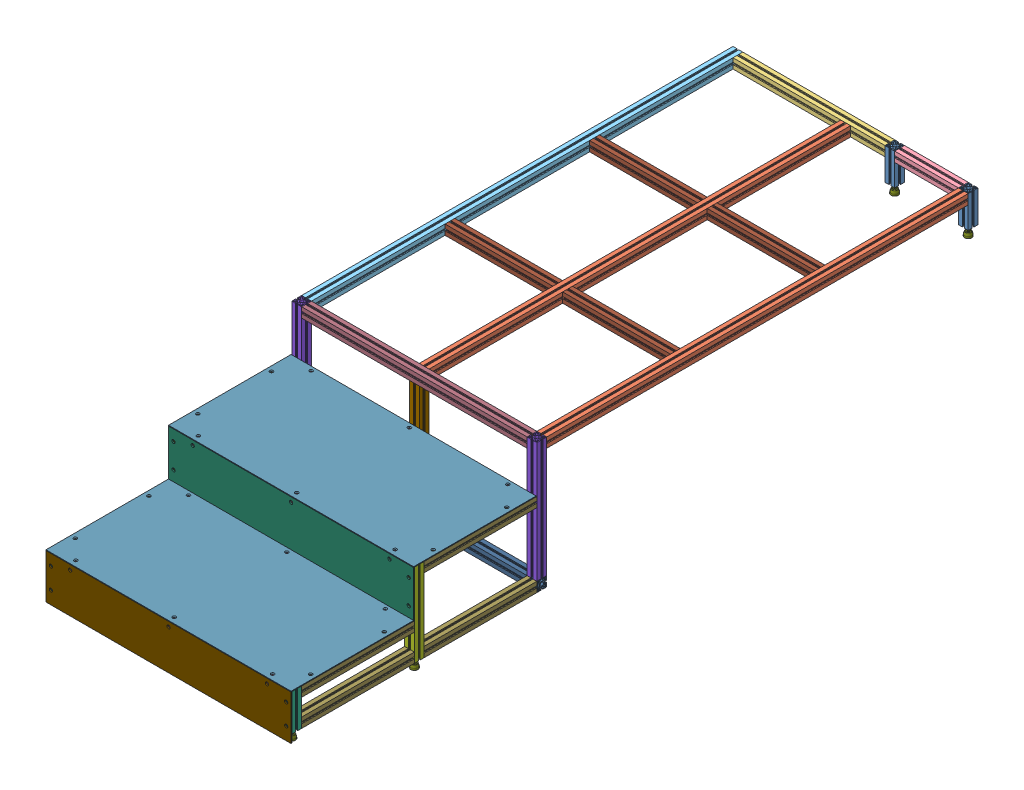
SolidWorks assembly LustroPd4 00-1-00, configuration Domyślna. Lengths in mm.
Overall size (1000 567 2803).
44 component instances, 18 part files, 0 mates.
Components (placement in the parent):
- LustroProfil 40x40x130-1: LustroProfil 40x40x130 [Default] at (20 -130 -1759.796) x (0 0 1) z (0 -1 0) size (40 40 130)
- LustroProfil 40x40x130-2: LustroProfil 40x40x130 [Default] at (-280 -130 -1759.796) x (0 0 1) z (0 -1 0) size (40 40 130)
- LustroProfil 40x40x1720-1: LustroProfil 40x40x1720 [Default] at (-20 -40 0) size (40 40 1720)
- LustroProfil 40x40x1720-2: LustroProfil 40x40x1720 [Default] at (-500 -40 0) size (40 40 1720)
- LustroProfil 40x40x620-1: LustroProfil 40x40x620 [Default] at (-940 -40 -1760) x (0 0 1) z (-1 0 0) size (40 40 620)
- LustroProfil 40x40x260-1: LustroProfil 40x40x260 [Default] at (-20 -40 -1720) x (0 0 -1) z (1 0 0) size (40 40 260)
- LustroProfil 40x40x1760-1: LustroProfil 40x40x1760 [Default] at (-980 -40 0) size (40 40 1760)
- LustroProfil 40x40x150-1: LustroProfil 40x40x150 [Default] at (-980 -380 1040) x (1 0 0) z (0 1 0) size (40 40 150)
- LustroProfil 40x40x150-2: LustroProfil 40x40x150 [Default] at (-20 -380 1040) x (1 0 0) z (0 1 0) size (40 40 150)
- LustroProfil 40x40x340-1: LustroProfil 40x40x340 [Default] at (-20 -530 500) x (1 0 0) z (0 -1 0) size (40 40 340)
- LustroProfil 40x40x340-2: LustroProfil 40x40x340 [Default] at (-980 -530 500) x (1 0 0) z (0 -1 0) size (40 40 340)
- LustroProfil 40x40x490-1: LustroProfil 40x40x490 [Default] at (-20 -490 0) x (1 0 0) z (0 -1 0) size (40 40 490)
- LustroProfil 40x40x490-2: LustroProfil 40x40x490 [Default] at (-980 -490 0) x (1 0 0) z (0 -1 0) size (40 40 490)
- LustroProfil 40x40x450-1: LustroProfil 40x40x450 [Default] at (-500 -490 0) x (1 0 0) z (0 -1 0) size (40 40 450)
- LustroProfil 40x40x1000-1: LustroProfil 40x40x1000 [Default] at (20 -530 40) x (0 0 -1) z (1 0 0) size (40 40 1000)
- LustroProfil 40x40x440-1: LustroProfil 40x40x440 [Default] at (-20 -40 -545) x (0 0 -1) z (1 0 0) size (40 40 440)
- LustroProfil 40x40x440-2: LustroProfil 40x40x440 [Default] at (-20 -40 -1135) x (0 0 -1) z (1 0 0) size (40 40 440)
- LustroProfil 40x40x440-3: LustroProfil 40x40x440 [Default] at (-500 -40 -1135) x (0 0 -1) z (1 0 0) size (40 40 440)
- LustroProfil 40x40x440-4: LustroProfil 40x40x440 [Default] at (-500 -40 -545) x (0 0 -1) z (1 0 0) size (40 40 440)
- LustroProfil 40x40x460-1: LustroProfil 40x40x460 [Default] at (-20 -420 1000) size (40 40 460)
- LustroProfil 40x40x460-2: LustroProfil 40x40x460 [Default] at (-980 -530 1000) size (40 40 460)
- LustroProfil 40x40x460-3: LustroProfil 40x40x460 [Default] at (-980 -420 1000) size (40 40 460)
- LustroProfil 40x40x460-4: LustroProfil 40x40x460 [Default] at (-980 -230 500) size (40 40 460)
- LustroProfil 40x40x460-5: LustroProfil 40x40x460 [Default] at (-20 -230 500) size (40 40 460)
- LustroProfil 40x40x460-6: LustroProfil 40x40x460 [Default] at (-980 -530 500) size (40 40 460)
- LustroProfil 40x40x460-7: LustroProfil 40x40x460 [Default] at (-20 -530 500) size (40 40 460)
- LustroProfil 40x40x460-8: LustroProfil 40x40x460 [Default] at (-20 -530 1000) size (40 40 460)
- LustroProfil 40x40x920-1: LustroProfil 40x40x920 [Default] at (-940 0 40) x (0 0 -1) z (-1 0 0) size (40 40 920)
- LustroProfil 40x40x920-2: LustroProfil 40x40x920 [Default] at (-940 -190 540) x (0 0 -1) z (-1 0 0) size (40 40 920)
- LustroProfil 40x40x920-3: LustroProfil 40x40x920 [Default] at (-940 -380 1040) x (0 0 -1) z (-1 0 0) size (40 40 920)
- LustroProfil 40x40x920-4: LustroProfil 40x40x920 [Default] at (-940 -380 580) x (0 0 -1) z (-1 0 0) size (40 40 920)
- LustroB28(1000x500)-1: LustroB28(1000x500) [Default] at (-480 -190 293) x (1 0 0) z (0 -1 0) size (1000 500 3)
- LustroB29(1000x190)-2: LustroB29(1000x190) [Default] at (-480 -285 540) x (-1 0 0) z (0 0 -1) size (1000 190 3)
- LustroB28(1000x500)-2: LustroB28(1000x500) [Default] at (-480 -380 793) x (1 0 0) z (0 -1 0) size (1000 500 3)
- Lustrob43-10-1: Lustrob43-10 [Domyślna] at (-960 -565 1020) x (0.92611 0 0.377253) z (-0.377253 0 0.92611) size (29 77 29)
- Lustrob43-10-2: Lustrob43-10 [Domyślna] at (0 -565 1020) x (0.341983 0 -0.939706) z (0.939706 0 0.341983) size (29 77 29)
- Lustrob43-10-3: Lustrob43-10 [Domyślna] at (-960 -565 520) x (0.341983 0 -0.939706) z (0.939706 0 0.341983) size (29 77 29)
- Lustrob43-10-4: Lustrob43-10 [Domyślna] at (0 -565 520) x (0.341983 0 -0.939706) z (0.939706 0 0.341983) size (29 77 29)
- Lustrob43-10-5: Lustrob43-10 [Domyślna] at (-300 -169 -1739.796) x (0.988522 0 -0.15108) z (0.15108 0 0.988522) size (29 77 29)
- Lustrob43-10-6: Lustrob43-10 [Domyślna] at (0 -169 -1739.796) size (29 77 29)
- LustroProfil 40x40x420-1: LustroProfil 40x40x420 [Default] at (-500 -420 1000) size (40 40 420)
- LustroProfil 40x40x920-5: LustroProfil 40x40x920 [Default] at (-940 -190 80) x (0 0 -1) z (-1 0 0) size (40 40 920)
- LustroProfil 40x40x420-2: LustroProfil 40x40x420 [Default] at (-500 -230 500) size (40 40 420)
- LustroB30(1000x182)-1: LustroB30(1000x182) [Domyślna] at (-480 -471 1043) size (1000 182 3)
